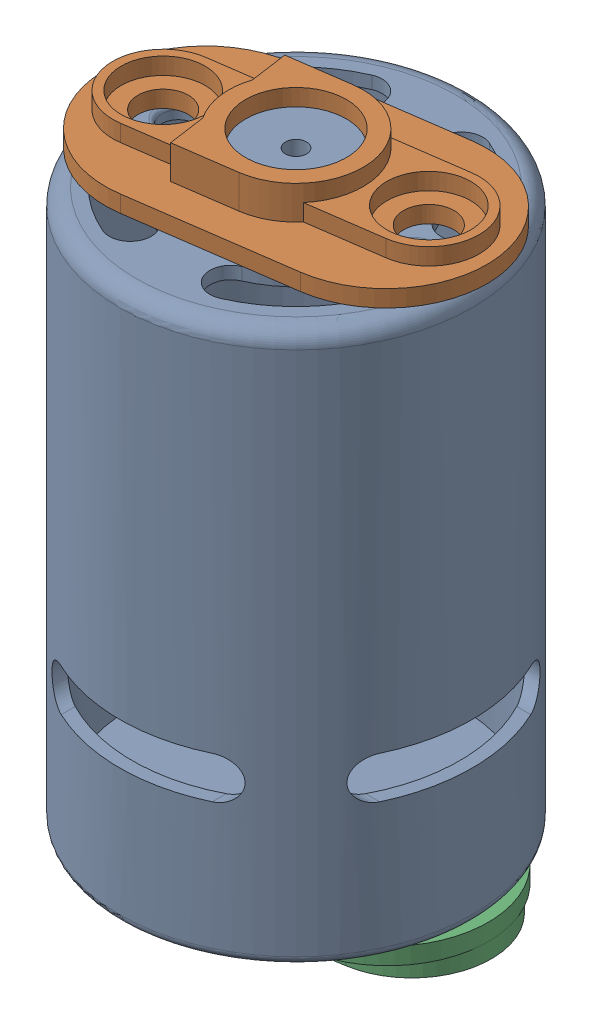
SolidWorks assembly Moteur, configuration Défaut. Lengths in mm.
Overall size (46.13 78 42).
3 component instances, 3 part files, 4 mates.
Components (placement in the parent):
- Stator-1: Stator [Défaut] at origin size (42 76 42)
- Silent bloc arrière-1: Silent bloc arrière [Défaut] at (-50.1525 74.546 -15.0185) x (-0.990107 0 0.140314) z (0 1 0) size (43 24 6)
- Silent bloc avant-1: Silent bloc avant [Défaut] at (43.3804 8.5648 -29.3082) x (0.986837 0 -0.161718) z (0 -1 0) size (41.91 24 4)
Mates (geometry in assembly coordinates):
- Coaxial1: concentric: cylinder of Stator-1; cylinder of Silent bloc arrière-1
- Coaxial2: concentric: cylinder of Stator-1; cylinder of Silent bloc avant-1
- Coïncidente1: coincident: plane of Stator-1 through (-17.5 8.5648 0) normal (0 -1 0); plane of Silent bloc avant-1 through (-9.375 8.5648 1.5363) normal (0 1 0)
- Coïncidente2: coincident: plane of Stator-1 through (-6 74.546 0) normal (0 1 0); plane of Silent bloc arrière-1 through (9.406 74.546 -1.333) normal (0 -1 0)
